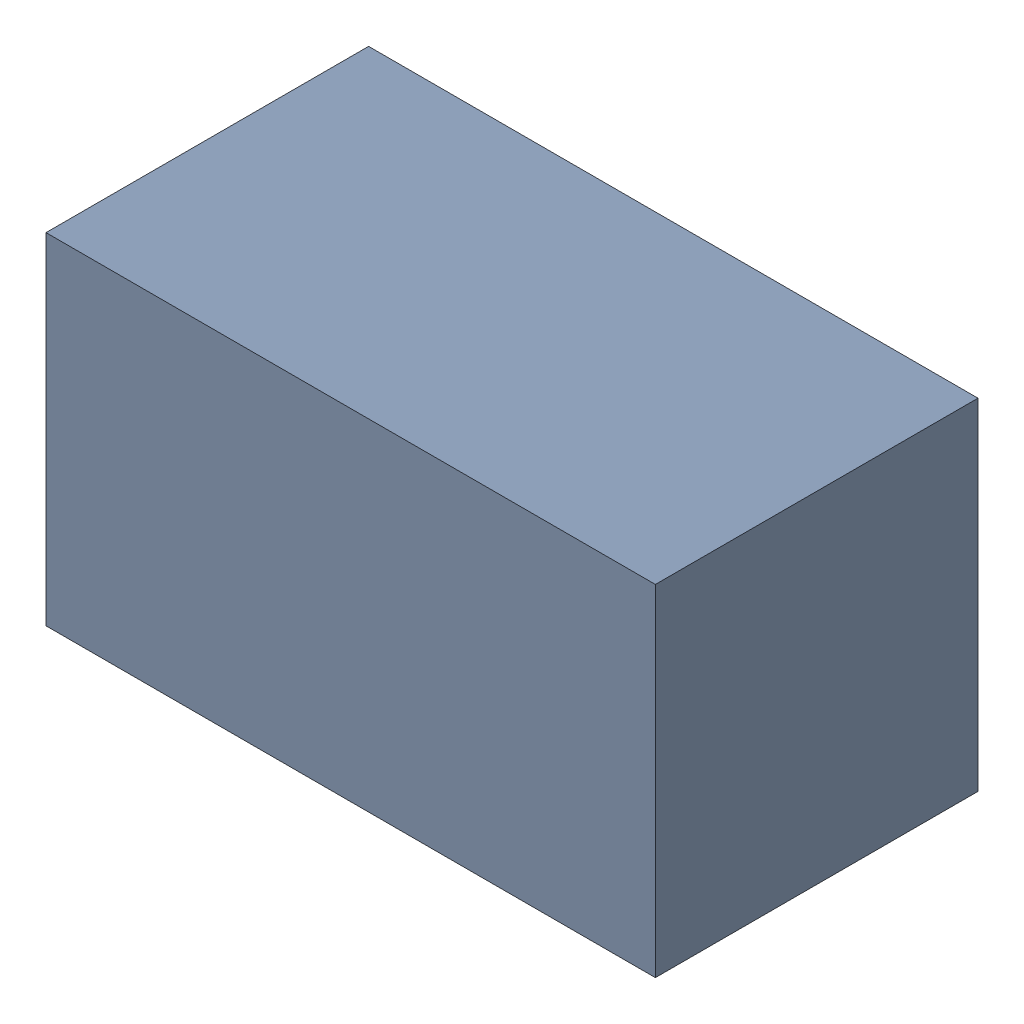
SolidWorks assembly R23, configuration Standard. Lengths in mm.
Overall size (1.7 0.95 0.9).
2 component instances, 1 part files, 0 mates.
Components (placement in the parent):
- 885541288-1: 885541288 [Standard] at (15.48 20.49 0) size (1.7 0.95 0.9)
  - Extruded_10-1: Extruded_10 [Standard] at origin size (1.7 0.95 0.9)
